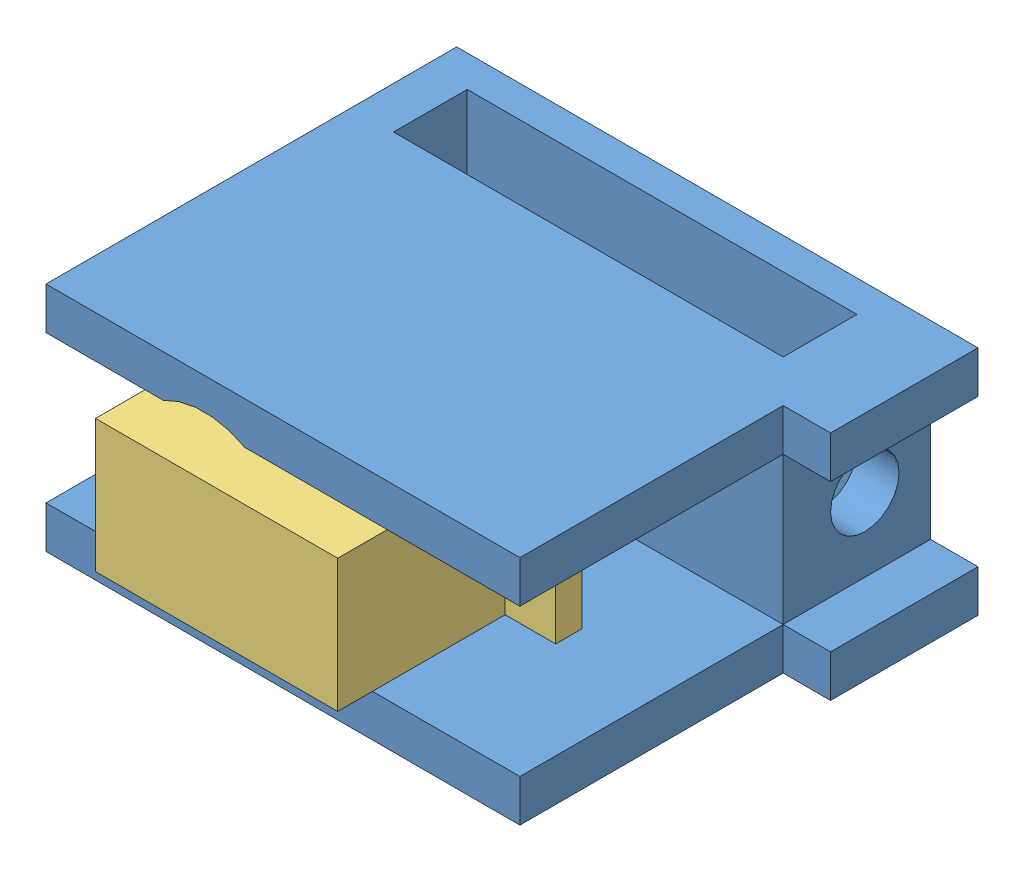
SolidWorks assembly A_Distributeur_2, configuration Défaut. Lengths in mm.
Overall size (49.5 22 43).
3 component instances, 3 part files, 5 mates.
Components (placement in the parent):
- socle-1: socle [Défaut] at (-24.6204 9.8379 35.5) size (49.5 22 39)
- Vis-1: Vis [Défaut] at (-9.6204 -1.1621 31.5) x (-0.159197 -0.987247 0) z (-0.987247 0.159197 0) size (13.7 10.52 14.01)
- servo-1: servo [Predeterminado] at (-4.4204 -7.4621 68.5) x (1 0 0) z (0 1 0) size (32.6 27 12.6)
Mates (geometry in assembly coordinates):
- Distance1: distance = 2 mm aligned: plane of socle-1 through (-24.6204 9.8379 39.5) normal (0 0 1); plane of Vis-1 through (-9.6204 -1.1621 41.5) normal (0 0 1)
- Coaxiale1: concentric anti-aligned: cylinder of socle-1 through (-9.6204 -1.1621 87.1274) axis (0 0 -1) radius 8; cylinder of Vis-1 through (-9.6204 -1.1621 36) axis (0 0 1) radius 2.5
- Coïncidente4: coincident anti-aligned: plane of Vis-1 through (-9.6204 -1.1621 41.5) normal (0 0 1); plane of servo-1 through (-4.4204 -7.4621 41.5) normal (0 0 -1)
- Coaxiale2: concentric anti-aligned: cylinder of socle-1 through (-9.6204 -1.1621 87.1274) axis (0 0 -1) radius 8; cylinder of servo-1 through (-9.6204 -1.1621 41.5) axis (0 0 1) radius 6.3
- Parallèle2: parallel anti-aligned: plane of socle-1 through (20.3796 5.8379 64.5) normal (0 -1 0); plane of servo-1 through (-4.4204 5.1379 68.5) normal (0 1 0)
